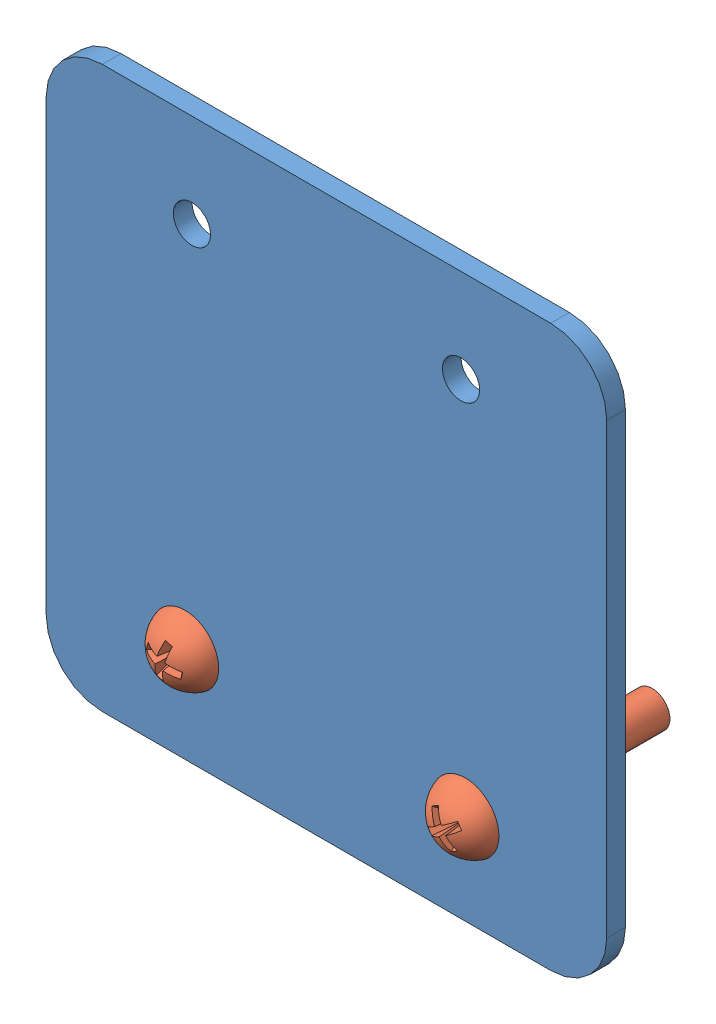
SolidWorks assembly lasercutter_bumer_base, configuration Default. Lengths in mm.
Overall size (76.2 76.2 28.82).
3 component instances, 2 part files, 4 mates.
Components (placement in the parent):
- laser_cutter_acrylic_base-1: laser_cutter_acrylic_base [Default] at (-64.1354 7.0035 27.8153) size (76.2 76.2 2.54)
- round head screw_ai-1: round head screw_ai [CR-RHMS 0.19-32x1x1-N] at (-83.3564 -18.1023 33.8351) x (0 0 -1) z (-0.245898 -0.969296 0) size (28.82 9.12 9.12)
- round head screw_ai-2: round head screw_ai [CR-RHMS 0.19-32x1x1-N] at (-45.258 -18.7858 33.8351) x (0 0 -1) z (-0.541576 0.840652 0) size (28.82 9.12 9.12)
Mates (geometry in assembly coordinates):
- Coincident1: coincident anti-aligned: plane of laser_cutter_acrylic_base-1 through (-102.2354 -31.0965 30.3553) normal (0 0 1); plane of round head screw_ai-2 through (-47.2865 -20.0926 30.3553) normal (0 0 -1)
- Coincident2: coincident anti-aligned: plane of laser_cutter_acrylic_base-1 through (-102.2354 -31.0965 30.3553) normal (0 0 1); plane of round head screw_ai-1 through (-81.0175 -18.6956 30.3553) normal (0 0 -1)
- Lock7: lock: unknown of laser_cutter_acrylic_base-1; unknown of round head screw_ai-1
- Lock8: lock: unknown of laser_cutter_acrylic_base-1; unknown of round head screw_ai-2
